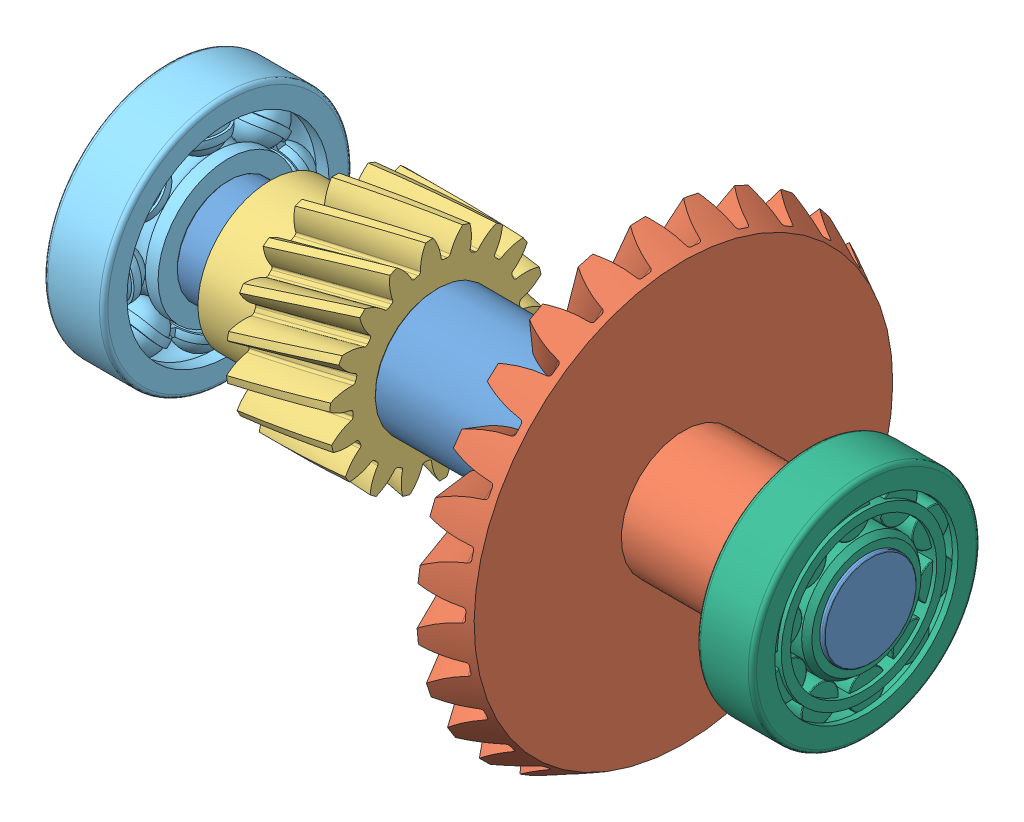
SolidWorks assembly Assem2, configuration Default. Lengths in mm.
Overall size (339 286.94 286.73).
7 component instances, 6 part files, 13 mates.
Components (placement in the parent):
- shaft2-1: shaft2 [Default] at (121.8135 193.7516 287.3385) x (1 0 0) z (0 0.931077 -0.364824) size (339 60 60)
- straight bevel gear_am-1: straight bevel gear_am [Metric - Straight bevel gear 8M 27GT 14PT 20PA 41.5FW ---27O60H121MD45R1] at (182.9357 185.543 266.3893) x (-1 0 0) z (0 -0.931077 0.364824) size (88.99 221.15 221.53)
- helical gear_3_am-1: helical gear_3_am [Metric - LH Helical gear 5M 18T 15HA 20PA 50FW ---18O70H80L50.0R1] at (13.7159 185.543 266.3893) x (1 0 0) z (0 0.931077 -0.364824) size (80 103.26 103.26)
- heavy duty external retaining ring_am-2: heavy duty external retaining ring_am [B27.8M - 3DM1-50] at (234.4024 185.543 266.3893) x (0 0.839381 -0.543544) z (-1 0 0) size (57.8 62.09 3.2)
- radial ball bearing_68_skf-1: radial ball bearing_68_skf [SKF - 6409 - 8,DE,AC,10_68] at (-51.2841 185.543 266.3893) x (1 0 0) z (0 -0.999998 -0.002032) size (29 120 120)
- heavy duty external retaining ring_am-3: heavy duty external retaining ring_am [B27.8M - 3DM1-50] at (-19.4841 185.543 266.3893) x (0 0.887875 0.460084) z (-1 0 0) size (57.8 62.09 3.2)
- radial cylindrical roller bearing_skf-1: radial cylindrical roller bearing_skf [SKF - NU 408 - 10,DE,AC,15] at (257.7159 185.543 266.3893) x (1 0 0) z (0 0.91747 0.397806) size (27 110 110)
Mates (geometry in assembly coordinates):
- Concentric1: concentric aligned: cylinder of shaft2-1 through (273.2159 185.543 266.3893) axis (1 0 0) radius 25; cylinder of straight bevel gear_am-1 through (61.9356 185.543 266.3893) axis (1 0 0) radius 22.5
- Coincident1: coincident anti-aligned: plane of shaft2-1 through (159.2159 174.5983 238.457) normal (1 0 0); plane of straight bevel gear_am-1 through (159.2159 185.543 266.3893) normal (-1 0 0)
- Concentric3: concentric anti-aligned: cylinder of shaft2-1 through (273.2159 185.543 266.3893) axis (1 0 0) radius 25; cylinder of helical gear_3_am-1 through (113.7159 185.543 266.3893) axis (-1 0 0) radius 25
- Parallel1: parallel anti-aligned: plane of shaft2-1 through (49.0616 178.429 248.2333) normal (0 -0.364824 -0.931077); plane of helical gear_3_am-1 through (113.7159 182.3023 236.1901) normal (0 0.364824 0.931077)
- Parallel2: parallel anti-aligned: plane of shaft2-1 through (224.8529 178.429 248.2333) normal (0 -0.364824 -0.931077); plane of straight bevel gear_am-1 through (61.9356 169.4306 244.4557) normal (0 0.364824 0.931077)
- Concentric5: concentric anti-aligned: cylinder of shaft2-1 through (273.2159 185.543 266.3893) axis (1 0 0) radius 23.5; cylinder of heavy duty external retaining ring_am-2 through (237.6024 185.543 266.3893) axis (-1 0 0) radius 23.5
- Concentric6: concentric aligned: cylinder of shaft2-1 through (273.2159 185.543 266.3893) axis (1 0 0) radius 22.5; cylinder of radial ball bearing_68_skf-1 through (-71.9216 185.543 266.3893) axis (1 0 0) radius 22.5
- Coincident8: coincident anti-aligned: plane of shaft2-1 through (-36.7841 177.3345 245.44) normal (-1 0 0); plane of radial ball bearing_68_skf-1 through (-36.7841 185.4252 324.3891) normal (1 0 0)
- Concentric8: concentric aligned: circle of shaft2-1; circle of heavy duty external retaining ring_am-3
- Coincident10: coincident anti-aligned: plane of shaft2-1 through (244.2159 176.4224 243.1123) normal (1 0 0); plane of radial cylindrical roller bearing_skf-1 through (244.2159 196.0227 242.2197) normal (-1 0 0)
- Concentric10: concentric aligned: cylinder of shaft2-1 through (273.2159 185.543 266.3893) axis (1 0 0) radius 22.5; cylinder of radial cylindrical roller bearing_skf-1 through (167.7159 185.543 266.3893) axis (1 0 0) radius 20
- Coincident12: coincident anti-aligned: plane of shaft2-1 through (63.7159 176.4224 243.1123) normal (-1 0 0); plane of helical gear_3_am-1 through (63.7159 185.543 266.3893) normal (1 0 0)
- Coincident13: coincident anti-aligned: plane of helical gear_3_am-1 through (-16.2841 185.543 266.3893) normal (-1 0 0); plane of heavy duty external retaining ring_am-3 through (-16.2841 185.543 266.3893) normal (1 0 0)
